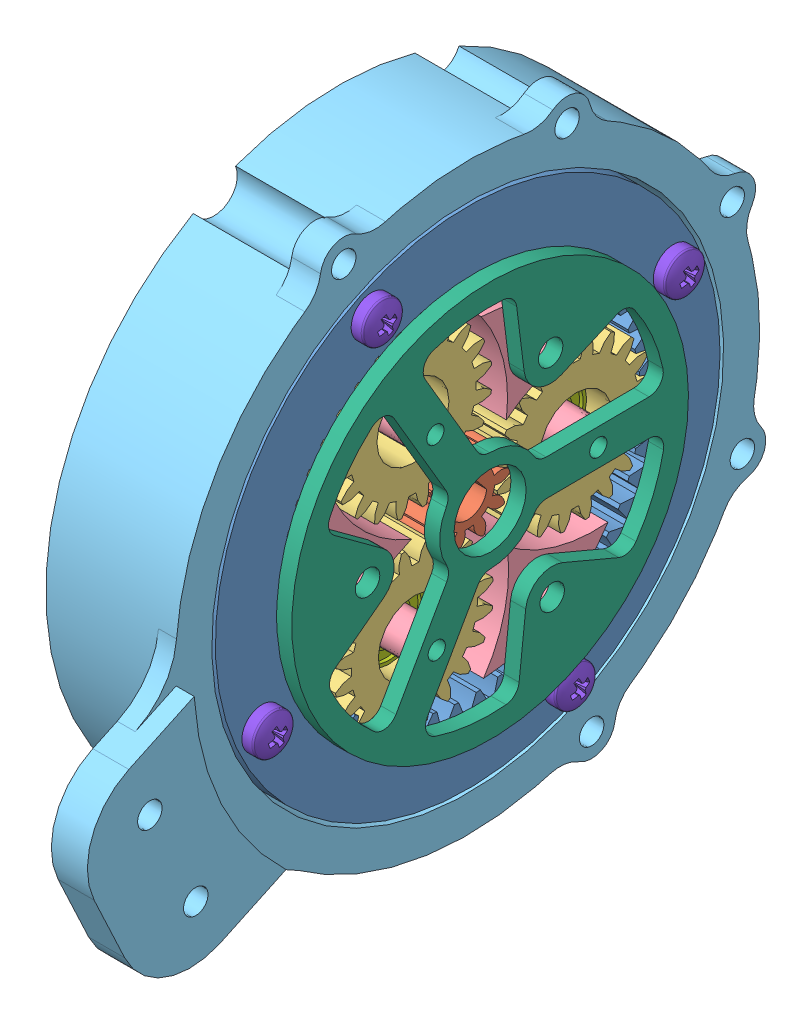
SolidWorks assembly ReductorDeRodillaEsnamble, configuration Predeterminado. Lengths in mm.
Overall size (23.11 122.25 128.92).
14 component instances, 8 part files, 59 mates.
Components (placement in the parent):
- anillo-15: anillo [ISO - Internal spur gear 1M 50T 20PA 10FW ---S50S70OD 1.0AF] at (25.094 2.7735 0) x (1 0 0) z (0 0.905496 0.424354) size (10 70 70)
- sol-2: sol [ISO - Spur gear 1M 10T 20PA 10FW ---S10A75H50L0.8N] at (25.094 2.7735 0) x (1 0 0) z (0 -0.637244 0.770662) size (20 11.48 12)
- Planeta-20: Planeta [ISO - Spur gear 1M 20T 20PA 10FW ---S20A75H50L0.8N] at (25.094 -10.2716 7.4045) x (1 0 0) z (0 -0.292495 0.956267) size (10 21.8 21.8)
- Planeta-18: Planeta [ISO - Spur gear 1M 20T 20PA 10FW ---S20A75H50L0.8N] at (25.094 2.8835 -14.9996) x (1 0 0) z (0 0.577293 -0.816537) size (10 21.8 21.8)
- Planeta-19: Planeta [ISO - Spur gear 1M 20T 20PA 10FW ---S20A75H50L0.8N] at (25.094 15.7085 7.5951) x (1 0 0) z (0 0.299258 -0.954172) size (10 21.8 21.8)
- PortaPlanetas-1: PortaPlanetas [Predeterminado] at (19.594 2.7735 0) x (0 0.493632 0.869671) z (0 0.869671 -0.493632) size (50.52 16.5 49.09)
- CampanaDeRodilla-1: CampanaDeRodilla [Predeterminado] at (26.094 2.7735 0) x (0 -0.905496 -0.424354) z (0 -0.424354 0.905496) size (87.5 20.5 101.37)
- TapaDeportaPlanetasReductorR-1: TapaDeportaPlanetasReductorR [Predeterminado] at (38.204 2.7735 0) x (0 0.999973 0.007338) z (0 -0.007338 0.999973) size (55 2.11 55)
- Rodamiento-2: Rodamiento [Predeterminado] at (31.594 2.8835 -14.9996) x (0 -0.461663 0.887055) z (0 -0.887055 -0.461663) size (10 3 10)
- Rodamiento-3: Rodamiento [Predeterminado] at (31.594 -10.2716 7.4045) x (0 0.729092 0.684416) z (0 -0.684416 0.729092) size (10 3 10)
- pan head cross recess screw_iso-10: pan head cross recess screw_iso [ISO 7045 - M3 x 20 - Z - 20N] at (37.494 31.2966 13.3671) x (-1 0 0) z (0 0.924225 0.381849) size (22.35 5.6 5.6)
- pan head cross recess screw_iso-11: pan head cross recess screw_iso [ISO 7045 - M3 x 20 - Z - 20N] at (37.494 -25.7497 -13.3671) x (-1 0 0) z (0 0.924225 0.381849) size (22.35 5.6 5.6)
- pan head cross recess screw_iso-12: pan head cross recess screw_iso [ISO 7045 - M3 x 20 - Z - 20N] at (37.494 16.1406 -28.5231) x (-1 0 0) z (0 -0.924225 -0.381849) size (22.35 5.6 5.6)
- pan head cross recess screw_iso-13: pan head cross recess screw_iso [ISO 7045 - M3 x 20 - Z - 20N] at (37.494 -10.5937 28.5231) x (-1 0 0) z (0 -0.924225 -0.381849) size (22.35 5.6 5.6)
Mates (geometry in assembly coordinates):
- Concéntrica1: concentric: circle of assembly; circle of assembly; circle of anillo-15; circle of PortaPlanetas-1
- Concéntrica2: concentric: circle of assembly; circle of Planeta-19; circle of PortaPlanetas-1
- Concéntrica3: concentric: circle of assembly; circle of Planeta-20; circle of PortaPlanetas-1
- Concéntrica4: concentric: circle of assembly; circle of Planeta-18; circle of PortaPlanetas-1
- Concéntrica5: concentric: circle of assembly; circle of PortaPlanetas-1; circle of sol-2
- Coincidente1: coincident: plane of assembly; plane of assembly; plane of anillo-15 through (35.094 -18.9584 -10.1845) normal (1 0 0); plane of Planeta-19 through (35.094 15.7085 7.5951) normal (1 0 0)
- Coincidente2: coincident: plane of assembly; plane of assembly; plane of anillo-15 through (35.094 -18.9584 -10.1845) normal (1 0 0); plane of Planeta-18 through (35.094 2.8835 -14.9996) normal (1 0 0)
- Coincidente3: coincident: plane of assembly; plane of assembly; plane of anillo-15 through (35.094 -18.9584 -10.1845) normal (1 0 0); plane of Planeta-20 through (35.094 -10.2716 7.4045) normal (1 0 0)
- Coincidente4: coincident: plane of assembly; plane of assembly; plane of anillo-15 through (35.094 -18.9584 -10.1845) normal (1 0 0); plane of sol-2 through (35.094 2.7735 0) normal (1 0 0)
- Relación de posición de engranaje2: gear = 10 : 20 mm: cylinder of Planeta-20 through (15.094 -10.2716 7.4045) axis (-1 0 0) radius 11; cylinder of sol-2 through (15.094 2.7735 0) axis (-1 0 0) radius 6
- Relación de posición de engranaje8: gear = 10 : 20 mm: cylinder of Planeta-19 through (15.094 15.7085 7.5951) axis (-1 0 0) radius 11; cylinder of sol-2 through (15.094 2.7735 0) axis (-1 0 0) radius 6
- Relación de posición de engranaje9: gear = 50 : 20 mm: cylinder of Planeta-19 through (15.094 15.7085 7.5951) axis (-1 0 0) radius 11; cylinder of anillo-15 through (15.094 2.7735 0) axis (-1 0 0) radius 24
- Distancia1: distance = 1 mm: plane of assembly; plane of assembly; plane of PortaPlanetas-1 through (24.094 2.7735 0) normal (1 0 0); plane of anillo-15 through (25.094 -18.9584 -10.1845) normal (-1 0 0)
- Concéntrica7: concentric: circle of PortaPlanetas-1; circle of TapaDeportaPlanetasReductorR-1
- Coincidente6: coincident: plane of assembly; plane of assembly; plane of PortaPlanetas-1 through (36.094 2.8835 -14.9996) normal (1 0 0); plane of TapaDeportaPlanetasReductorR-1 through (36.094 2.7735 0) normal (-1 0 0)
- Concéntrica8: concentric: circle of PortaPlanetas-1; circle of TapaDeportaPlanetasReductorR-1
- Concéntrica11: concentric: cylinder of CampanaDeRodilla-1 through (25.094 -10.5937 28.5231) axis (-1 0 0) radius 1.7; cylinder of ? through (68.394 17.9897 -27.5811) axis (1 0 0) radius 2.8
- Coincidente9: coincident: plane of CampanaDeRodilla-1 through (25.094 2.7735 0) normal (1 0 0); plane of ? through (40.594 17.4169 -26.1948) normal (-1 0 0)
- Concéntrica12: concentric: cylinder of ? through (68.394 17.9897 -27.5811) axis (1 0 0) radius 1.5; cylinder of ? through (0.7428 17.9897 -27.5811) axis (1 0 0) radius 1.5
- Concéntrica16: concentric: point of ?; cylinder of ? through (-3.606 13.4432 29.6379) axis (-1 0 0) radius 2.8
- Coincidente11: coincident: plane of anillo-15 through (25.094 -18.9584 -10.1845) normal (-1 0 0); plane of ? through (24.194 14.9432 29.6379) normal (1 0 0)
- Concéntrica17: concentric: cylinder of CampanaDeRodilla-1 through (25.094 -10.5937 28.5231) axis (-1 0 0) radius 1.7; cylinder of ? through (15.9565 13.4432 29.6379) axis (1 0 0) radius 1.5
- Coincidente12: coincident: plane of CampanaDeRodilla-1 through (25.094 2.7735 0) normal (1 0 0); plane of ? through (39.194 12.2307 32.5727) normal (-1 0 0)
- Concéntrica18: concentric: cylinder of CampanaDeRodilla-1 through (25.094 -25.7497 -13.3671) axis (-1 0 0) radius 1.7; cylinder of ? through (15.9565 -28.2286 -5.5787) axis (1 0 0) radius 1.5
- Coincidente13: coincident: plane of CampanaDeRodilla-1 through (25.094 2.7735 0) normal (1 0 0); plane of ? through (39.194 -31.404 -5.5787) normal (-1 0 0)
- Concéntrica19: concentric: cylinder of CampanaDeRodilla-1 through (25.094 16.1406 -28.5231) axis (-1 0 0) radius 1.7; cylinder of ? through (15.9565 23.1058 -24.0592) axis (1 0 0) radius 1.5
- Coincidente14: coincident: plane of CampanaDeRodilla-1 through (25.094 2.7735 0) normal (1 0 0); plane of ? through (39.194 26.2713 -23.8086) normal (-1 0 0)
- Concéntrica20: concentric: cylinder of anillo-15 through (39.0023 -28.2286 -5.5787) axis (-1 0 0) radius 1.7; cylinder of ? through (-3.606 -28.2286 -5.5787) axis (-1 0 0) radius 2.8
- Coincidente15: coincident: plane of anillo-15 through (25.094 -18.9584 -10.1845) normal (-1 0 0); plane of ? through (24.194 -26.7286 -5.5787) normal (1 0 0)
- Concéntrica21: concentric: cylinder of anillo-15 through (39.0023 23.1058 -24.0592) axis (-1 0 0) radius 1.7; cylinder of ? through (-3.606 23.1058 -24.0592) axis (-1 0 0) radius 2.8
- Coincidente16: coincident: plane of anillo-15 through (25.094 -18.9584 -10.1845) normal (-1 0 0); plane of ? through (24.194 24.6058 -24.0593) normal (1 0 0)
- Concéntrica23: concentric: cylinder of ? through (36.094 2.0107 -14.9806) axis (1 0 0) radius 1.2; cylinder of ? through (-5.206 -3.2103 13.7548) axis (-1 0 0) radius 2
- Coincidente18: coincident: plane of ? through (21.794 2.0107 -14.9806) normal (-1 0 0); plane of ? through (21.794 -2.2103 13.7548) normal (1 0 0)
- Concéntrica24: concentric: cylinder of ? through (36.094 16.1285 6.8297) axis (1 0 0) radius 1.2; cylinder of ? through (-5.206 -6.1466 -12.0595) axis (-1 0 0) radius 2
- Coincidente19: coincident: plane of ? through (21.794 16.1285 6.8297) normal (-1 0 0); plane of ? through (21.794 -7.0918 -11.733) normal (1 0 0)
- Concéntrica25: concentric: cylinder of ? through (36.094 -9.8187 8.1509) axis (1 0 0) radius 1.2; cylinder of ? through (-5.206 17.6774 -1.6953) axis (-1 0 0) radius 2
- Coincidente20: coincident: plane of ? through (21.794 -9.8187 8.1509) normal (-1 0 0); plane of ? through (21.794 16.6774 -1.6953) normal (1 0 0)
- Concéntrica27: concentric: unknown of PortaPlanetas-1; unknown of ?
- Ancho2: width: plane of ? through (29.094 -6.1466 -12.0595) normal (-1 0 0); plane of ? through (31.094 -6.1466 -12.0595) normal (1 0 0); plane of ? through (35.094 16.1285 6.8297) normal (1 0 0); plane of ? through (25.094 16.1285 6.8297) normal (-1 0 0)
- Concéntrica28: concentric: circle of assembly; circle of Planeta-20; circle of Rodamiento-3
- Concéntrica29: concentric: circle of assembly; circle of assembly; circle of PortaPlanetas-1; circle of Rodamiento-2
- Ancho3: width: plane of assembly; plane of assembly; plane of assembly; plane of assembly; plane of Rodamiento-2 through (31.094 2.8835 -14.9996) normal (1 0 0); plane of Rodamiento-2 through (29.094 2.8835 -14.9996) normal (-1 0 0); plane of Planeta-18 through (35.094 2.8835 -14.9996) normal (1 0 0); plane of Planeta-18 through (25.094 2.8835 -14.9996) normal (-1 0 0)
- Ancho4: width: plane of assembly; plane of assembly; plane of assembly; plane of assembly; plane of Rodamiento-3 through (31.094 -10.2716 7.4045) normal (1 0 0); plane of Rodamiento-3 through (29.094 -10.2716 7.4045) normal (-1 0 0); plane of Planeta-19 through (35.094 15.7085 7.5951) normal (1 0 0); plane of Planeta-19 through (25.094 15.7085 7.5951) normal (-1 0 0)
- Relación de posición de engranaje10: gear = 20 : 10 mm: cylinder of sol-2 through (15.094 2.7735 0) axis (-1 0 0) radius 6; cylinder of Planeta-18 through (15.094 2.8835 -14.9996) axis (-1 0 0) radius 11
- Concéntrica30: concentric: unknown of ?; unknown of PortaPlanetas-1
- Concéntrica31: concentric: circle of ?; circle of ?
- Concéntrica36: concentric: circle of PortaPlanetas-1; circle of ?
- Concéntrica37: concentric: circle of ?; circle of ?
- Coincidente21: coincident: plane of assembly; plane of assembly; plane of anillo-15 through (25.094 -18.9584 -10.1845) normal (-1 0 0); plane of CampanaDeRodilla-1 through (25.094 2.7735 0) normal (1 0 0)
- Concéntrica38: concentric: circle of assembly; circle of assembly; circle of CampanaDeRodilla-1; circle of TapaDeportaPlanetasReductorR-1
- Concéntrica39: concentric: circle of assembly; circle of anillo-15; circle of CampanaDeRodilla-1
- Concéntrica40: concentric: cylinder of assembly; cylinder of anillo-15 through (39.9023 31.2966 13.3671) axis (-1 0 0) radius 1.7; cylinder of pan head cross recess screw_iso-10 through (62.894 31.2966 13.3671) axis (1 0 0) radius 2.8
- Coincidente22: coincident: plane of anillo-15 through (35.094 -18.9584 -10.1845) normal (1 0 0); plane of pan head cross recess screw_iso-10 through (35.094 30.7238 14.7535) normal (-1 0 0)
- Concéntrica41: concentric: cylinder of assembly; cylinder of anillo-15 through (39.9023 -25.7497 -13.3671) axis (-1 0 0) radius 1.7; cylinder of pan head cross recess screw_iso-11 through (62.894 -25.7497 -13.3671) axis (1 0 0) radius 2.8
- Coincidente23: coincident: plane of anillo-15 through (35.094 -18.9584 -10.1845) normal (1 0 0); plane of pan head cross recess screw_iso-11 through (35.094 -26.3224 -11.9808) normal (-1 0 0)
- Concéntrica42: concentric: cylinder of assembly; cylinder of pan head cross recess screw_iso-12 through (62.894 16.1406 -28.5231) axis (1 0 0) radius 2.8; circle of anillo-15
- Coincidente24: coincident: plane of assembly; plane of assembly; plane of anillo-15 through (35.094 -18.9584 -10.1845) normal (1 0 0); plane of pan head cross recess screw_iso-12 through (35.094 16.7134 -29.9095) normal (-1 0 0)
- Concéntrica43: concentric: cylinder of assembly; cylinder of pan head cross recess screw_iso-13 through (62.894 -10.5937 28.5231) axis (1 0 0) radius 2.8; circle of anillo-15
- Coincidente25: coincident: plane of assembly; plane of assembly; plane of anillo-15 through (35.094 -18.9584 -10.1845) normal (1 0 0); plane of pan head cross recess screw_iso-13 through (35.094 -10.0209 27.1368) normal (-1 0 0)
